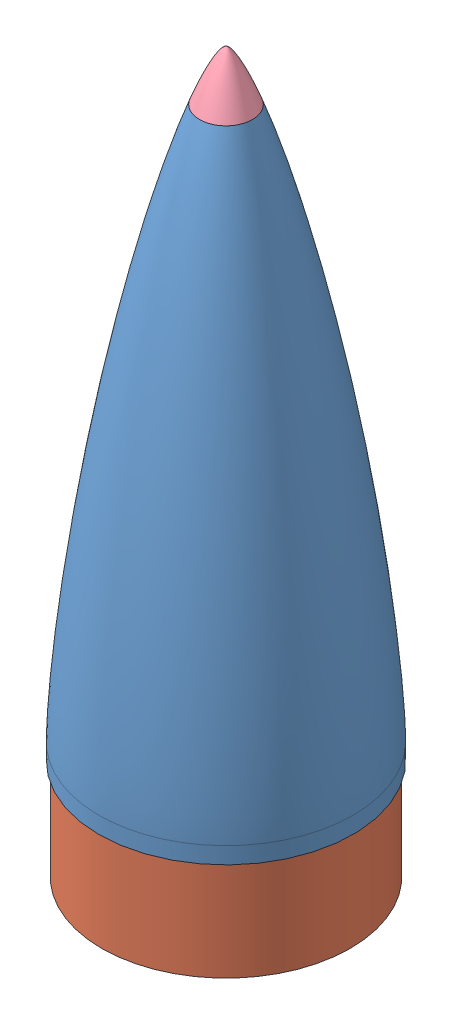
SolidWorks assembly Von Karman Assembly, configuration Default. Lengths in mm.
Overall size (193.68 547.71 193.68).
5 component instances, 5 part files, 4 mates.
Components (placement in the parent):
- Von Karman NoseCone-1: Von Karman NoseCone [Default] x (0 -1 0) z (0 0 1) size (433.41 193.68 193.68)
- NoseCone Coupler-3: NoseCone Coupler [Default] at (0 -546.1 0) size (190.5 88.9 190.5)
- Von Karman NoseCone Base-3: Von Karman NoseCone Base [Default] at (0 0 0) x (0 -1 0) z (0 0 1) size (19.05 49.04 49.04)
- Von Karman NoseCone Tip-2: Von Karman NoseCone Tip [Default] x (0 -1 0) z (0 0 1) size (38.1 40.2 40.2)
- 3014T450_STEEL EYEBOLT WITH SHOULDER - FOR LIFTING-2: 3014T450_STEEL EYEBOLT WITH SHOULDER - FOR LIFTING [3014T45] at (0.3283 -77.729 0.094) x (-1 0 0) z (0 0 1) size (30.16 64.79 14.29)
Mates (geometry in assembly coordinates):
- Coincident10: coincident: circle of Von Karman NoseCone-1; circle of NoseCone Coupler-3
- Coincident12: coincident: circle of Von Karman NoseCone-1; circle of Von Karman NoseCone Base-3
- Coincident13: coincident: circle of Von Karman NoseCone-1; circle of Von Karman NoseCone Tip-2
- Tangent1: tangent: circle of Von Karman NoseCone Base-3; curve of 3014T450_STEEL EYEBOLT WITH SHOULDER - FOR LIFTING-2
